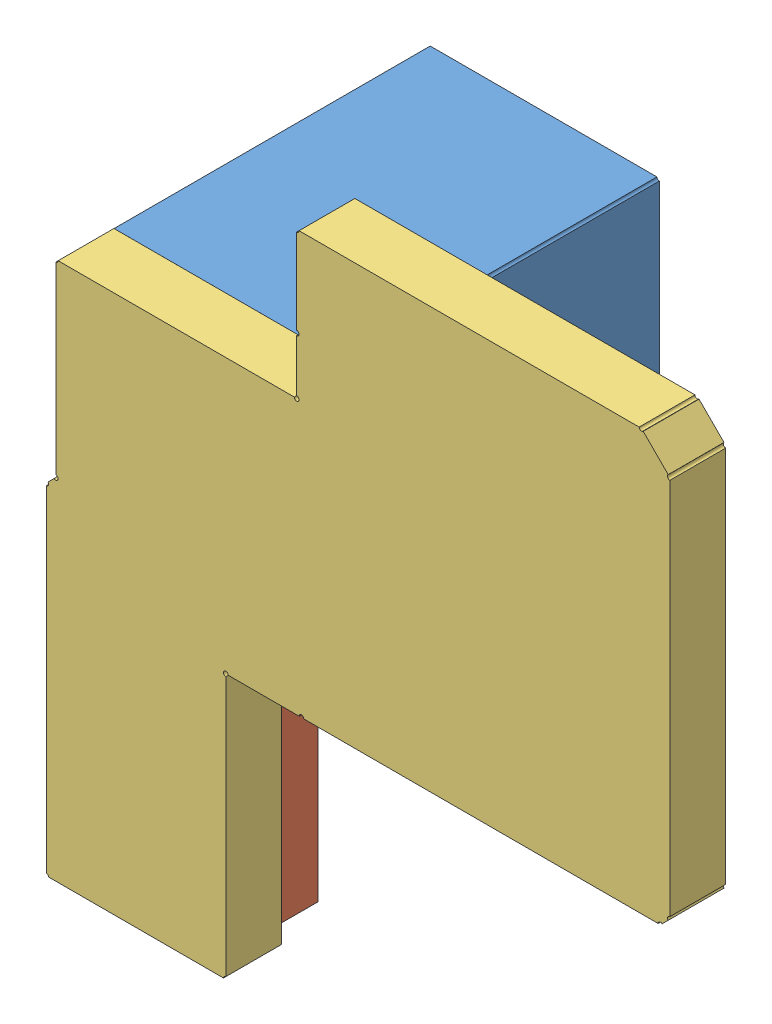
SolidWorks assembly 装配体1, configuration 默认. Lengths in mm.
Overall size (16.76 18.42 10).
3 component instances, 3 part files, 0 mates.
Components (placement in the parent):
- DRMOS导热快-1: DRMOS导热快 [默认] at (-95.018 -88.7472 4.25) size (6.22 5.08 8.5)
- LT3935导热块-1: LT3935导热块 [默认] at (-95.018 -88.7498 11.262) size (4.32 5.33 1.5)
- 顶部导热块-1: 顶部导热块 [默认] at (-95.0176 -88.744 12.7534) size (16.76 18.41 1.5)
